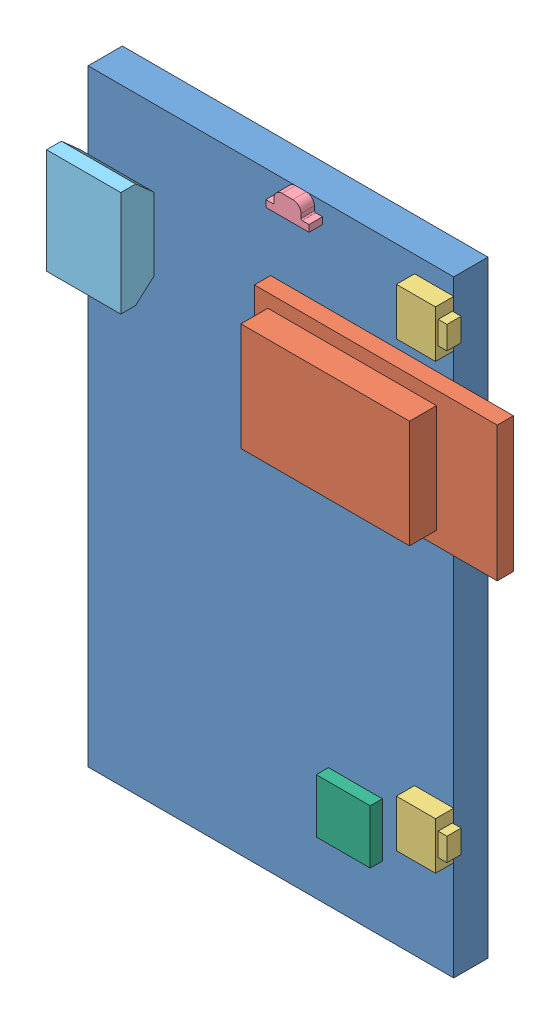
SolidWorks assembly PCB Assembly, configuration Default. Lengths in mm.
Overall size (32.15 45 5.74).
7 component instances, 6 part files, 22 mates.
Components (placement in the parent):
- Mainboard-1: Mainboard [Default] at (13.55 -45 2.54) x (-1 0 0) z (0 0 -1) size (27.1 45 2.54)
- BLE Module-1: BLE Module [Default] at (8.975 -11.7 3.74) x (-1 0 0) z (0 1 0) size (18 3.2 10)
- Tactile Switch PTS840-2: Tactile Switch PTS840 [Default] at (13.55 -3 3.89) x (0 1 0) z (1 0 0) size (3.5 1.35 3.55)
- Tactile Switch PTS840-3: Tactile Switch PTS840 [Default] at (13.55 -35.85 3.89) x (0 1 0) z (1 0 0) size (3.5 1.35 3.55)
- RGB LED-1: RGB LED [Default] at (2.225 -1.25 3.54) x (1 0 0) z (0 1 0) size (3.2 1 1.5)
- USB Connector micro B smd-1: USB Connector micro B smd [Default] at (-8.675 -8.375 2.54) x (0 -1 0) z (-1 0 0) size (7.8 2.45 5.5)
- MPU-6050-1: MPU-6050 [Default] at (6.262 -38.142 2.54) x (1 0 0) z (0 -1 0) size (4 0.9 4)
Mates (geometry in assembly coordinates):
- Coincident5: coincident: moEndPointRef_w of Mainboard-1; plane of assembly
- Coincident6: coincident aligned: plane of Mainboard-1 through (13.55 0 0) normal (0 1 0); plane of assembly through (0 0 0) normal (0 1 0)
- Coincident7: coincident anti-aligned: plane of Mainboard-1 through (13.55 -45 0) normal (0 0 -1); plane of assembly through (0 0 0) normal (0 0 1)
- Coincident8: coincident anti-aligned: plane of Mainboard-1 through (13.55 -45 2.54) normal (0 0 1); plane of BLE Module-1 through (8.975 -11.7 2.54) normal (0 0 -1)
- Distance2: distance = 4.425 mm aligned: plane of Mainboard-1 through (13.55 -45 0) normal (1 0 0); plane of BLE Module-1 through (17.975 -16.7 2.54) normal (1 0 0)
- Coincident17: coincident anti-aligned: plane of Mainboard-1 through (13.55 -45 2.54) normal (0 0 1); plane of Tactile Switch PTS840-2 through (10.65 -4.75 2.54) normal (0 0 -1)
- Coincident19: coincident anti-aligned: plane of Mainboard-1 through (13.55 -45 2.54) normal (0 0 1); plane of Tactile Switch PTS840-3 through (10.65 -37.6 2.54) normal (0 0 -1)
- Coincident21: coincident aligned: plane of Mainboard-1 through (13.55 -45 0) normal (1 0 0); plane of Tactile Switch PTS840-2 through (13.55 -3 3.89) normal (1 0 0)
- Coincident22: coincident aligned: plane of Mainboard-1 through (13.55 -45 0) normal (1 0 0); plane of Tactile Switch PTS840-3 through (13.55 -35.85 3.89) normal (1 0 0)
- Distance6: distance = 9.15 mm: point of Mainboard-1; moEndPointRef_w of Tactile Switch PTS840-3
- Coincident24: coincident aligned: plane of Mainboard-1 through (13.55 0 0) normal (0 1 0); plane of RGB LED-1 through (2.625 0 2.54) normal (0 1 0)
- Coincident25: coincident anti-aligned: plane of Mainboard-1 through (13.55 -45 2.54) normal (0 0 1); plane of RGB LED-1 through (1.125 -0.9 2.54) normal (0 0 -1)
- Distance8: distance = 15.775 mm: point of Mainboard-1; moEndPointRef_w of RGB LED-1
- Coincident26: coincident anti-aligned: plane of Mainboard-1 through (13.55 -45 2.54) normal (0 0 1); plane of USB Connector micro B smd-1 through (-14.175 -5.675 2.54) normal (0 0 -1)
- Distance9: distance = 0.625 mm aligned: plane of USB Connector micro B smd-1 through (-14.175 -8.375 2.54) normal (-1 0 0); plane of Mainboard-1 through (-13.55 -45 0) normal (-1 0 0)
- Coincident27: coincident: plane of Mainboard-1 through (13.55 -45 2.54) normal (0 0 1); plane of MPU-6050-1 through (6.1076 -38.2964 2.54) normal (0 0 -1)
- Distance13: distance = 32.85 mm: moEndPointRef_w of Tactile Switch PTS840-2; moEndPointRef_w of Tactile Switch PTS840-3
- Distance14: distance = 28.3 mm aligned: plane of BLE Module-1 through (-0.025 -16.7 2.54) normal (0 -1 0); plane of Mainboard-1 through (13.55 -45 0) normal (0 -1 0)
- Distance15: distance = 19.812 mm: moEndPointRef_w of MPU-6050-1; line of Mainboard-1 through (-13.55 -45 2.54) axis (0 1 0)
- Distance16: distance = 6.858 mm: moEndPointRef_w of MPU-6050-1; line of Mainboard-1 through (13.55 -45 2.54) axis (-1 0 0)
- Distance17: distance = 8.375 mm: moEndPointRef_w of USB Connector micro B smd-1; line of Mainboard-1 through (-13.55 0 2.54) axis (1 0 0)
- Parallel1: parallel aligned: plane of Mainboard-1 through (-13.55 -45 0) normal (-1 0 0); plane of MPU-6050-1 through (4.262 -36.142 3.44) normal (-1 0 0)
